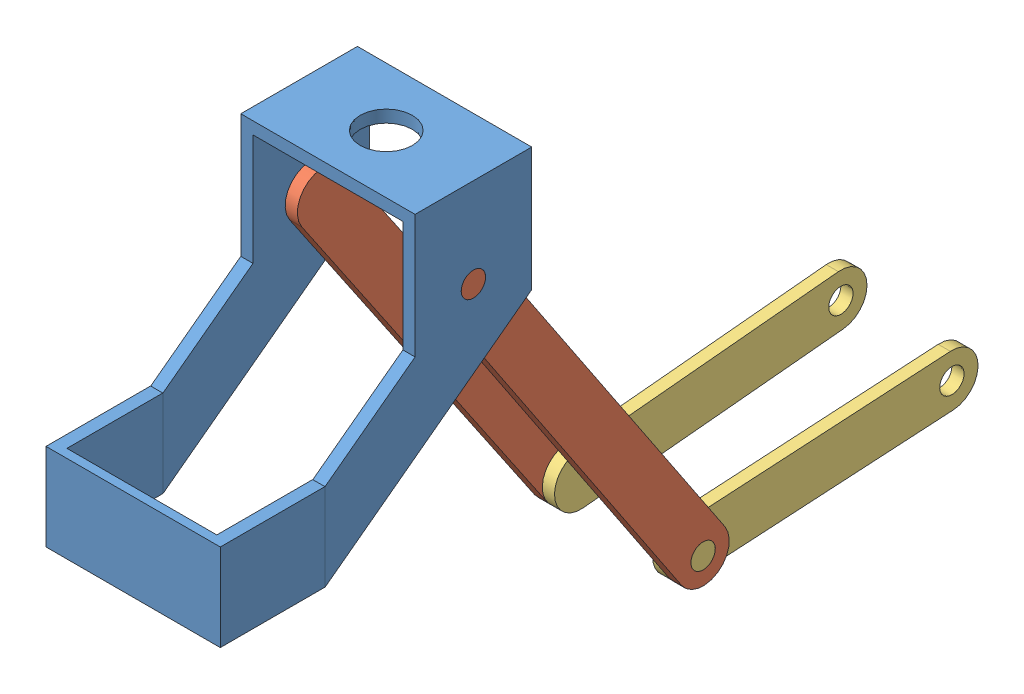
SolidWorks assembly Assem1, configuration Default. Lengths in mm.
Overall size (100.07 280.1 451.35).
5 component instances, 3 part files, 8 mates.
Components (placement in the parent):
- Part1-1: Part1 [Default] at (-9.3458 31.2509 255.094) size (100.07 159.46 178.61)
- Part2-1: Part2 [Default] at (28.1542 25.9176 45.5539) x (0 0.831735 0.555174) z (1 0 0) size (280 30 14)
- Part2-2: Part2 [Default] at (-43.8458 26.5015 44.6871) x (0 0.827064 0.562108) z (-1 0 0) size (280 30 14)
- Part3-1: Part3 [Default] at (28.1542 -73.7011 -98.7166) x (0 -0.057975 0.998318) z (-1 0 0) size (180 30 14)
- Part3-2: Part3 [Default] at (-43.8458 -69.729 -100.2346) x (0 -0.095366 0.995442) z (1 0 0) size (180 30 14)
Mates (geometry in assembly coordinates):
- Coincident1: coincident anti-aligned: plane of Part1-1 through (35.1542 31.2509 255.094) normal (-1 0 0); plane of Part2-1 through (35.1542 -78.0492 -23.8428) normal (1 0 0)
- Concentric1: concentric aligned: cylinder of Part1-1 through (42.1542 129.8845 114.9506) axis (-1 0 0) radius 7; cylinder of Part2-1 through (42.1542 129.8845 114.9506) axis (-1 0 0) radius 7
- Coincident2: coincident anti-aligned: plane of Part1-1 through (-50.8458 31.2509 255.094) normal (1 0 0); plane of Part2-2 through (-50.8458 -76.8815 -25.5764) normal (-1 0 0)
- Concentric2: concentric anti-aligned: cylinder of Part1-1 through (42.1542 129.8845 114.9506) axis (-1 0 0) radius 7; cylinder of Part2-2 through (-57.8458 129.8845 114.9506) axis (1 0 0) radius 7
- Coincident3: coincident anti-aligned: plane of Part2-1 through (28.1542 -78.0492 -23.8428) normal (-1 0 0); plane of Part3-1 through (28.1542 -69.3529 -173.5905) normal (1 0 0)
- Concentric3: concentric anti-aligned: cylinder of Part2-1 through (28.1542 -78.0492 -23.8428) axis (1 0 0) radius 7; cylinder of Part3-1 through (35.1542 -78.0492 -23.8428) axis (-1 0 0) radius 7
- Coincident4: coincident anti-aligned: plane of Part2-2 through (-43.8458 -76.8815 -25.5764) normal (1 0 0); plane of Part3-2 through (-43.8458 -62.5766 -174.8928) normal (-1 0 0)
- Concentric4: concentric anti-aligned: cylinder of Part2-2 through (-43.8458 -76.8815 -25.5764) axis (-1 0 0) radius 7; cylinder of Part3-2 through (-50.8458 -76.8815 -25.5764) axis (1 0 0) radius 7
